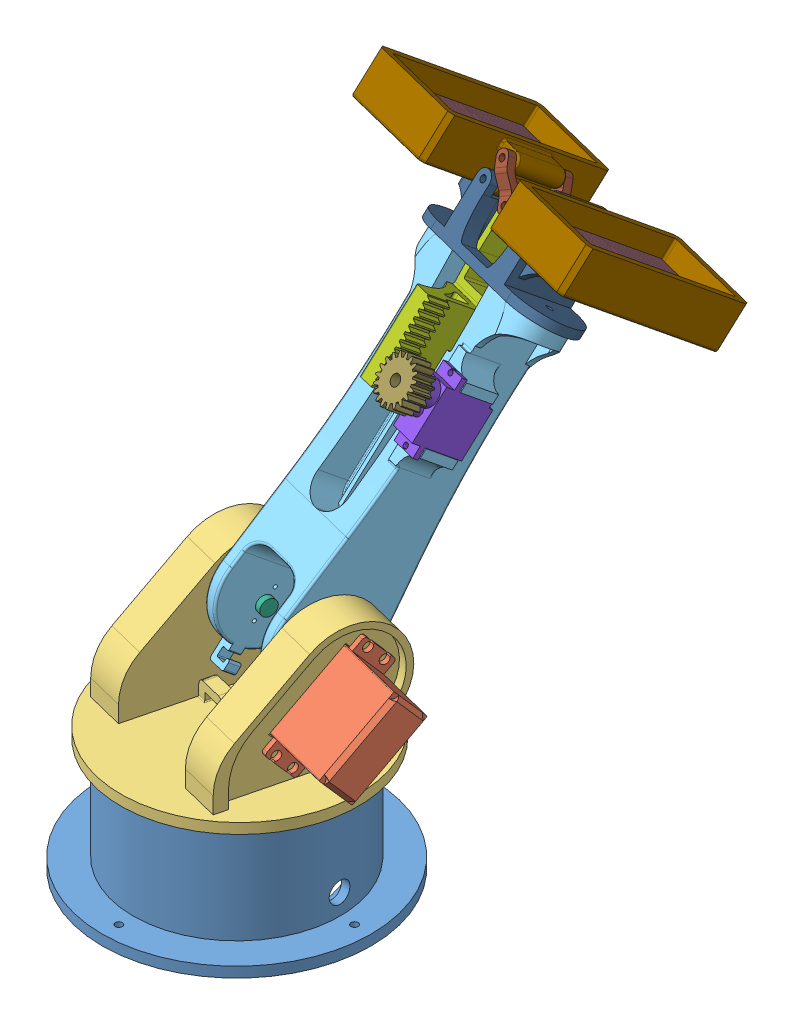
SolidWorks assembly Locking Assembly_V11, configuration Default. Lengths in mm.
Overall size (183.33 345.45 244.34).
20 component instances, 13 part files, 54 mates.
Components (placement in the parent):
- Robot Base-1: Robot Base [Default] at (43.8926 39.741 102.4347) size (130 55.6 130)
- ##Servo_MG_996R-1: ##Servo_MG_996R [Default] at (35.3562 47.341 102.4347) size (53.6 45.5 20)
- Waist_V3-1: Waist_V3 [Default] at (45.3562 95.341 102.4347) x (0.243056 0 -0.970012) z (0.970012 0 0.243056) size (115 64.46 115)
- Circle Rudder-1: Circle Rudder [默认] at (45.3562 95.341 102.4347) x (-0.243056 0 0.970012) z (0.970012 0 0.243056) size (20.8 5.5 20.8)
- ##Servo_MG_996R-2: ##Servo_MG_996R [Default] at (116.7376 127.8535 107.8209) x (0.182292 0.661438 -0.727509) z (-0.160767 0.75 0.641603) size (53.6 45.5 20)
- Robot Arm_V3-1: Robot Arm_V3 [Default] at (29.4624 138.4808 75.1456) x (0.970012 0 0.243056) z (-0.195075 0.59653 0.778523) size (74 170.33 46)
- Circle Rudder-2: Circle Rudder [默认] at (69.4779 134.4678 88.2472) x (0.195075 -0.59653 -0.778523) z (-0.14499 -0.802591 0.578641) size (20.8 5.5 20.8)
- Waist lock-1: Waist lock [Default] at (24.1783 134.4678 76.8965) x (0.970012 0 0.243056) z (-0.243056 -0.000001 0.970012) size (27 13.4 13.4)
- Sliding panel_V2-1: Sliding panel_V2 [Default] at (56.839 243.875 41.087) x (-0.14499 -0.802591 0.578641) z (-0.195075 0.59653 0.778523) size (76 25 45)
- SG90 Servo-1: SG90 Servo [Default] at (89.396 216.1877 39.6131) x (-0.14499 -0.802591 0.578641) z (-0.970012 0 -0.243056) size (33 31.3 12.5)
- L_Solar Panel Mount_V3-1: L_Solar Panel Mount_V3 [Default] at (31.3273 283.0412 -35.154) x (0.970012 0 0.243056) z (-0.195075 0.59653 0.778523) size (60 20.05 80)
- Panel Mount_V2-1: Panel Mount_V2 [Default] at (70.4382 252.5428 -1.985) x (0.970012 0 0.243056) z (-0.195075 0.59653 0.778523) size (83 30 33.18)
- L_Solar Panel Mount_V3-2: L_Solar Panel Mount_V3 [Default] at (120.5684 283.0412 -12.7928) x (-0.970012 0 -0.243056) z (0.195075 -0.59653 -0.778523) size (60 20.05 80)
- Joint connecter-1: Joint connecter [Default] at (60.3046 284.7903 -8.6816) x (0.428465 -0.662191 0.614753) z (-0.195075 0.59653 0.778523) size (22.93 6 8)
- Joint connecter-2: Joint connecter [Default] at (66.547 265.7014 -33.5943) x (0.428465 -0.662191 0.614753) z (0.195075 -0.59653 -0.778523) size (22.93 6 8)
- Joint connecter-3: Joint connecter [Default] at (88.7746 265.7014 -28.0248) x (-0.667718 -0.662191 0.340082) z (0.195075 -0.59653 -0.778523) size (22.93 6 8)
- Joint connecter-4: Joint connecter [Default] at (79.4667 275.4303 -6.9841) x (0.667718 0.662191 -0.340082) z (0.195075 -0.59653 -0.778523) size (22.93 6 8)
- Bevel Gear-1: Bevel Gear [Default] at (233.2433 -113.1457 74.6786) x (-0.195075 0.59653 0.778523) z (-0.332475 -0.786994 0.519712) size (180.31 117.5 139.1)
- 0.5V Epoxy Solar Cell-1: 0.5V Epoxy Solar Cell [Default] at (29.8774 275.0153 -29.3676) x (-0.195075 0.59653 0.778523) z (-0.970012 0 -0.243056) size (65 3 35)
- 0.5V Epoxy Solar Cell-2: 0.5V Epoxy Solar Cell [Default] at (119.1185 275.0153 -7.0064) x (-0.195075 0.59653 0.778523) z (-0.970012 0 -0.243056) size (65 3 35)
Mates (geometry in assembly coordinates):
- Parallel1: parallel anti-aligned: plane of Robot Base-1 through (56.3562 -9.6553 89.4347) normal (-1 0 0); plane of ##Servo_MG_996R-1 through (55.3562 85.341 92.4347) normal (1 0 0)
- Distance2: distance = 1 mm anti-aligned: plane of ##Servo_MG_996R-1 through (15.3562 85.341 92.4347) normal (-1 0 0); plane of Robot Base-1 through (14.3562 -9.6553 115.4347) normal (1 0 0)
- Coincident3: coincident anti-aligned: plane of Robot Base-1 through (64.3562 77.741 115.4347) normal (0 1 0); plane of ##Servo_MG_996R-1 through (35.3562 77.741 102.4347) normal (0 -1 0)
- Distance3: distance = 3 mm aligned: plane of ##Servo_MG_996R-1 through (15.3562 85.341 92.4347) normal (0 0 -1); plane of Robot Base-1 through (64.3562 77.741 89.4347) normal (0 0 -1)
- Concentric1: concentric anti-aligned: cylinder of ##Servo_MG_996R-1 through (45.3562 92.841 102.4347) axis (0 -1 0) radius 3; cylinder of Circle Rudder-1 through (45.3562 89.841 102.4347) axis (0 1 0) radius 3
- Distance4: distance = 1 mm anti-aligned: plane of Circle Rudder-1 through (45.3562 89.841 102.4347) normal (0 -1 0); plane of ##Servo_MG_996R-1 through (45.3562 88.841 102.4347) normal (0 1 0)
- Concentric2: concentric anti-aligned: cylinder of Waist_V3-1 through (45.3562 97.341 102.4347) axis (0 -1 0) radius 3.75; cylinder of Circle Rudder-1 through (45.3562 93.041 102.4347) axis (0 1 0) radius 1.5
- Coincident6: coincident anti-aligned: plane of Waist_V3-1 through (45.3562 95.341 102.4347) normal (0 -1 0); plane of Circle Rudder-1 through (45.3562 95.341 102.4347) normal (0 1 0)
- Distance5: distance = 0.5 mm anti-aligned: plane of ##Servo_MG_996R-2 through (85.1307 133.5822 77.6186) normal (0.182292 0.661438 -0.727509); plane of Waist_V3-1 through (73.875 149.2879 88.3903) normal (-0.182292 -0.661438 0.727509)
- Distance6: distance = 0.5 mm anti-aligned: plane of ##Servo_MG_996R-2 through (74.6236 122.1247 119.551) normal (-0.160767 0.75 0.641603); plane of Waist_V3-1 through (73.875 149.2879 88.3903) normal (0.160767 -0.75 -0.641603)
- Coincident9: coincident: plane of Waist_V3-1 through (90.3889 108.341 71.8564) normal (0.970012 0 0.243056); line of ##Servo_MG_996R-2 through (87.1924 140.7072 84.6131) axis (-0.160767 0.75 0.641603)
- Concentric3: concentric anti-aligned: cylinder of Waist_V3-1 through (47.0576 159.7996 95.6446) axis (0 -1 0) radius 0.85; cylinder of Circle Rudder-1 through (47.0576 93.041 95.6446) axis (0 1 0) radius 0.75
- Concentric4: concentric aligned: cylinder of Robot Arm_V3-1 through (69.4779 134.4678 88.2472) axis (-0.970012 0 -0.243056) radius 3.75; cylinder of Circle Rudder-2 through (71.7089 134.4678 88.8062) axis (-0.970012 0 -0.243056) radius 1.5
- Concentric5: concentric anti-aligned: cylinder of ##Servo_MG_996R-2 through (74.425 134.4678 89.4868) axis (0.970012 0 0.243056) radius 3; cylinder of Circle Rudder-2 through (74.813 134.4678 89.584) axis (-0.970012 0 -0.243056) radius 3
- Coincident10: coincident anti-aligned: plane of Waist_V3-1 through (71.8001 134.7986 88.4425) normal (-0.970012 0 -0.243056); plane of Circle Rudder-2 through (71.7089 134.4678 88.8062) normal (0.970012 0 0.243056)
- Coincident12: coincident anti-aligned: plane of Robot Arm_V3-1 through (70.2029 138.4808 85.354) normal (0.970012 0 0.243056); plane of Circle Rudder-2 through (69.4779 134.4678 88.2472) normal (-0.970012 0 -0.243056)
- Concentric10: concentric anti-aligned: cylinder of Waist_V3-1 through (4.6747 134.4678 72.0094) axis (0.970012 0 0.243056) radius 3.75; cylinder of Waist lock-1 through (24.1783 134.4678 76.8965) axis (-0.970012 0 -0.243056) radius 3.7
- Coincident14: coincident anti-aligned: plane of Waist_V3-1 through (20.063 108.341 54.2348) normal (-0.970012 0 -0.243056); plane of Waist lock-1 through (14.9632 141.1678 74.5875) normal (0.970012 0 0.243056)
- Coincident15: coincident anti-aligned: plane of Robot Arm_V3-1 through (40.1325 138.4808 77.8193) normal (0.970012 0 0.243056); plane of Sliding panel_V2-1 through (49.7797 243.875 39.3181) normal (-0.970012 0 -0.243056)
- Distance7: distance = 0.5 mm anti-aligned: plane of Robot Arm_V3-1 through (49.0207 164.0163 64.9759) normal (-0.195075 0.59653 0.778523); plane of Sliding panel_V2-1 through (61.9773 249.9995 2.9816) normal (0.195075 -0.59653 -0.778523)
- Coincident23: coincident anti-aligned: plane of Robot Arm_V3-1 through (82.0327 230.7862 38.1425) normal (-0.14499 -0.802591 0.578641); plane of SG90 Servo-1 through (77.1826 230.7862 36.9272) normal (0.14499 0.802591 -0.578641)
- Coincident21: coincident anti-aligned: plane of Robot Arm_V3-1 through (91.5326 240.4173 33.1433) normal (-0.195075 0.59653 0.778523); plane of SG90 Servo-1 through (77.1826 230.7862 36.9272) normal (0.195075 -0.59653 -0.778523)
- Coincident22: coincident aligned: plane of Robot Arm_V3-1 through (78.9225 240.4173 29.9835) normal (-0.970012 0 -0.243056); plane of SG90 Servo-1 through (77.2709 216.1877 36.5749) normal (-0.970012 0 -0.243056)
- Concentric11: concentric aligned: cylinder of Robot Arm_V3-1 through (39.7981 233.2806 5.0968) axis (0.14499 0.802591 -0.578641) radius 1.5; cylinder of Panel Mount_V2-1 through (42.6979 249.3324 -6.4761) axis (0.14499 0.802591 -0.578641) radius 1.5
- Concentric12: concentric aligned: cylinder of Robot Arm_V3-1 through (94.1188 233.2806 18.7079) axis (0.14499 0.802591 -0.578641) radius 1.5; cylinder of Panel Mount_V2-1 through (97.0186 249.3324 7.1351) axis (0.14499 0.802591 -0.578641) radius 1.5
- Coincident24: coincident anti-aligned: plane of Robot Arm_V3-1 through (-56.5336 258.2804 -18.9295) normal (0.14499 0.802591 -0.578641); plane of Panel Mount_V2-1 through (45.608 249.3324 -5.7469) normal (-0.14499 -0.802591 0.578641)
- Concentric13: concentric aligned: cylinder of L_Solar Panel Mount_V3-1 through (55.7669 277.3581 -9.2618) axis (0.195075 -0.59653 -0.778523) radius 1.5; cylinder of Panel Mount_V2-1 through (54.8891 280.0425 -5.7584) axis (0.195075 -0.59653 -0.778523) radius 1.5
- Distance8: distance = 0.5 mm anti-aligned: plane of L_Solar Panel Mount_V3-1 through (51.1598 278.1607 -11.0311) normal (-0.195075 0.59653 0.778523); plane of Panel Mount_V2-1 through (52.3683 280.8668 -12.1595) normal (0.195075 -0.59653 -0.778523)
- Concentric14: concentric anti-aligned: cylinder of Panel Mount_V2-1 through (85.9295 280.0425 2.0194) axis (0.195075 -0.59653 -0.778523) radius 1.5; cylinder of L_Solar Panel Mount_V3-2 through (91.4891 263.0414 -20.1685) axis (-0.195075 0.59653 0.778523) radius 1.5
- Distance9: distance = 0.5 mm anti-aligned: plane of L_Solar Panel Mount_V3-2 through (91.7044 278.1607 -0.8719) normal (-0.195075 0.59653 0.778523); plane of Panel Mount_V2-1 through (91.1708 280.8668 -2.4368) normal (0.195075 -0.59653 -0.778523)
- Concentric15: concentric anti-aligned: cylinder of L_Solar Panel Mount_V3-1 through (59.1568 285.3841 -14.5621) axis (0.195075 -0.59653 -0.778523) radius 1.5; cylinder of Joint connecter-1 through (59.9371 282.9979 -17.6762) axis (-0.195075 0.59653 0.778523) radius 1.5
- Concentric16: concentric aligned: cylinder of Sliding panel_V2-1 through (69.883 262.9059 -20.3406) axis (-0.195075 0.59653 0.778523) radius 1.5; cylinder of Joint connecter-1 through (66.7618 272.4504 -7.8843) axis (-0.195075 0.59653 0.778523) radius 1.5
- Coincident27: coincident anti-aligned: plane of L_Solar Panel Mount_V3-1 through (54.2598 284.5815 -15.1742) normal (-0.195075 0.59653 0.778523); plane of Joint connecter-1 through (63.2725 284.4744 -12.8338) normal (0.195075 -0.59653 -0.778523)
- Concentric17: concentric aligned: cylinder of L_Solar Panel Mount_V3-1 through (59.1568 285.3841 -14.5621) axis (0.195075 -0.59653 -0.778523) radius 1.5; cylinder of Joint connecter-2 through (63.0583 273.4535 -30.1325) axis (0.195075 -0.59653 -0.778523) radius 1.5
- Concentric18: concentric anti-aligned: cylinder of Sliding panel_V2-1 through (69.883 262.9059 -20.3406) axis (-0.195075 0.59653 0.778523) radius 1.5; cylinder of Joint connecter-2 through (69.883 262.9059 -20.3406) axis (0.195075 -0.59653 -0.778523) radius 1.5
- Coincident28: coincident anti-aligned: plane of L_Solar Panel Mount_V3-1 through (58.9416 270.2648 -33.8587) normal (0.195075 -0.59653 -0.778523); plane of Joint connecter-2 through (62.6608 267.4367 -30.7599) normal (-0.195075 0.59653 0.778523)
- Concentric19: concentric anti-aligned: cylinder of L_Solar Panel Mount_V3-2 through (90.999 271.0673 -26.4411) axis (-0.195075 0.59653 0.778523) radius 1.5; cylinder of Joint connecter-3 through (90.2187 273.4535 -23.327) axis (0.195075 -0.59653 -0.778523) radius 1.5
- Concentric20: concentric anti-aligned: cylinder of Sliding panel_V2-1 through (79.5831 262.9059 -17.9101) axis (-0.195075 0.59653 0.778523) radius 1.5; cylinder of Joint connecter-3 through (79.5831 262.9059 -17.9101) axis (0.195075 -0.59653 -0.778523) radius 1.5
- Coincident29: coincident anti-aligned: plane of L_Solar Panel Mount_V3-2 through (95.6061 270.2648 -24.6717) normal (0.195075 -0.59653 -0.778523); plane of Joint connecter-3 through (86.5547 270.1577 -26.8577) normal (-0.195075 0.59653 0.778523)
- Concentric21: concentric anti-aligned: cylinder of L_Solar Panel Mount_V3-2 through (90.999 271.0673 -26.4411) axis (-0.195075 0.59653 0.778523) radius 1.5; cylinder of Joint connecter-4 through (85.5369 287.7702 -4.6424) axis (0.195075 -0.59653 -0.778523) radius 1.5
- Concentric22: concentric anti-aligned: cylinder of Sliding panel_V2-1 through (79.5831 262.9059 -17.9101) axis (-0.195075 0.59653 0.778523) radius 1.5; cylinder of Joint connecter-4 through (74.9013 277.2227 0.7745) axis (0.195075 -0.59653 -0.778523) radius 1.5
- Coincident30: coincident anti-aligned: plane of L_Solar Panel Mount_V3-2 through (90.9243 284.5815 -5.9871) normal (-0.195075 0.59653 0.778523); plane of Joint connecter-4 through (86.1833 281.7535 -5.0082) normal (0.195075 -0.59653 -0.778523)
- Concentric23: concentric aligned: cylinder of SG90 Servo-1 through (79.817 234.1052 52.1279) axis (0.195075 -0.59653 -0.778523) radius 2.5; cylinder of Bevel Gear-1 through (69.3415 266.1388 93.9346) axis (0.195075 -0.59653 -0.778523) radius 2.5
- Distance14: distance = 3 mm: plane of SG90 Servo-1 through (79.7582 229.9241 52.3625) normal (-0.195075 0.59653 0.778523); point of Bevel Gear-1
- Coincident33: coincident anti-aligned: plane of L_Solar Panel Mount_V3-1 through (29.8774 275.0153 -29.3676) normal (0.14499 0.802591 -0.578641); plane of 0.5V Epoxy Solar Cell-1 through (29.8774 275.0153 -29.3676) normal (-0.14499 -0.802591 0.578641)
- Distance10: distance = 3.5 mm anti-aligned: plane of 0.5V Epoxy Solar Cell-1 through (53.6275 258.0359 -52.152) normal (0.195075 -0.59653 -0.778523); plane of L_Solar Panel Mount_V3-1 through (12.1699 245.5144 -57.4414) normal (-0.195075 0.59653 0.778523)
- Distance11: distance = 2.5 mm anti-aligned: plane of 0.5V Epoxy Solar Cell-1 through (53.6275 258.0359 -52.152) normal (0.970012 0 0.243056); plane of L_Solar Panel Mount_V3-1 through (55.6307 243.1282 -49.861) normal (-0.970012 0 -0.243056)
- Coincident36: coincident anti-aligned: plane of L_Solar Panel Mount_V3-2 through (119.1185 275.0153 -7.0064) normal (0.14499 0.802591 -0.578641); plane of 0.5V Epoxy Solar Cell-2 through (119.1185 275.0153 -7.0064) normal (-0.14499 -0.802591 0.578641)
- Distance12: distance = 3.5 mm anti-aligned: plane of 0.5V Epoxy Solar Cell-2 through (142.8686 258.0359 -29.7908) normal (0.195075 -0.59653 -0.778523); plane of L_Solar Panel Mount_V3-2 through (147.9716 245.5144 -23.4135) normal (-0.195075 0.59653 0.778523)
- Distance13: distance = 2.5 mm anti-aligned: plane of 0.5V Epoxy Solar Cell-2 through (142.8686 258.0359 -29.7908) normal (0.970012 0 0.243056); plane of L_Solar Panel Mount_V3-2 through (129.2659 290.8506 34.782) normal (-0.970012 0 -0.243056)
- Concentric24: concentric aligned: cylinder of Robot Arm_V3-1 through (70.4928 140.086 84.1967) axis (-0.970012 0 -0.243056) radius 0.85; cylinder of Circle Rudder-2 through (72.7239 140.086 84.7557) axis (-0.970012 0 -0.243056) radius 0.75
- RackPinionMate1: rack pinion = 19 mm: cylinder of Sliding panel_V2-1 through (22.959 190.3277 81.3152) axis (0.14499 0.802591 -0.578641) radius 29.8245; circle of Bevel Gear-1
- LimitAngle1: limit planar angle = 0 rad anti-aligned: plane of Panel Mount_V2-1 through (90.0108 274.446 2.1923) normal (0.14499 0.802591 -0.578641); plane of L_Solar Panel Mount_V3-2 through (117.6686 266.9894 -1.22) normal (-0.14499 -0.802591 0.578641)
- LimitAngle2: limit planar angle = 2.209967 rad anti-aligned: plane of Waist_V3-1 through (45.3562 100.341 102.4347) normal (0 1 0); plane of Robot Arm_V3-1 through (29.4624 138.4808 75.1456) normal (-0.195075 0.59653 0.778523)
